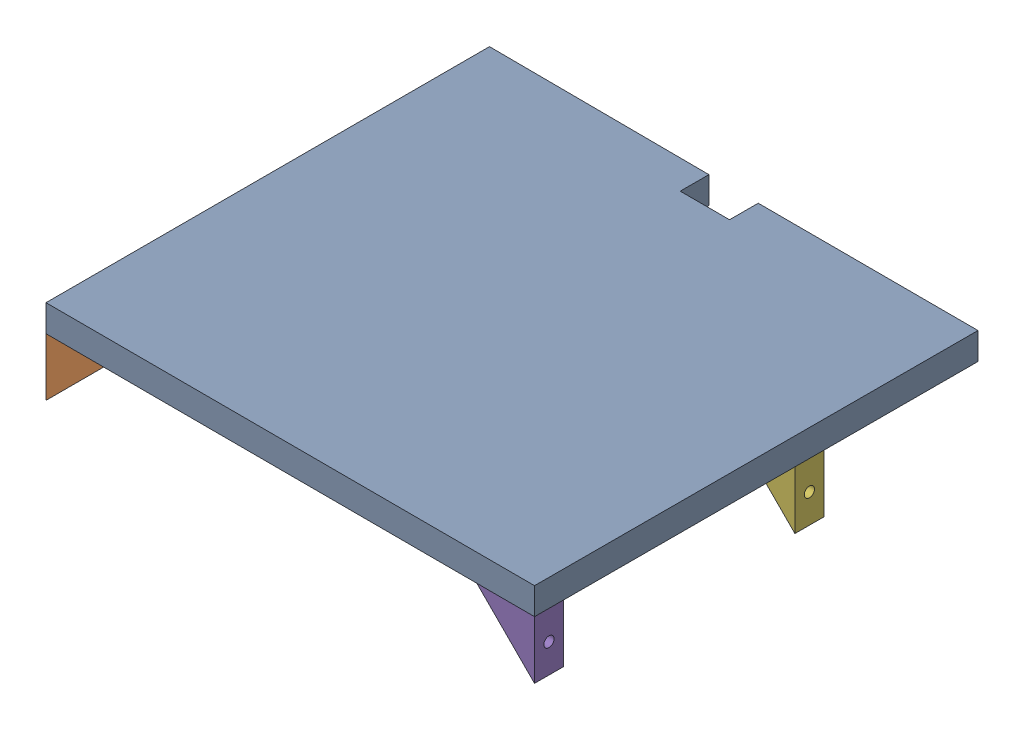
SolidWorks assembly body-top-electronics-plate, configuration Default. Lengths in mm.
Overall size (215.83 37.21 195.37).
7 component instances, 2 part files, 15 mates.
Components (placement in the parent):
- body-top-electronics-plate-1: body-top-electronics-plate [Default] at (150.8544 -10.5013 -261.1673) x (0.999999 0 0.001709) z (-0.001709 0 0.999999) size (215.5 11.81 195)
- body-top-electronics-bracket-1: body-top-electronics-bracket [Default] at (150.8651 -10.5013 -72.475) size (25.4 25.4 12.7)
- body-top-electronics-bracket-7: body-top-electronics-bracket [Default] at (150.8651 -10.5013 -186.775) size (25.4 25.4 12.7)
- body-top-electronics-bracket-8: body-top-electronics-bracket [Default] at (85.1809 -10.5013 -159.0477) x (-0.005146 0 0.999987) z (-0.999987 0 -0.005146) size (25.4 25.4 12.7)
- body-top-electronics-bracket-13: body-top-electronics-bracket [Default] at (149.6443 -10.5013 -84.9893) x (-0.999999 0 -0.001709) z (0.001709 0 -0.999999) size (25.4 25.4 12.7)
- body-top-electronics-bracket-14: body-top-electronics-bracket [Default] at (149.8397 -10.5013 -199.2892) x (-0.999999 0 -0.001709) z (0.001709 0 -0.999999) size (25.4 25.4 12.7)
- body-top-electronics-bracket-15: body-top-electronics-bracket [Default] at (197.2535 -10.5013 -158.6702) x (-0.001709 0 0.999999) z (-0.999999 0 -0.001709) size (25.4 25.4 12.7)
Mates (geometry in assembly coordinates):
- Coincident1: coincident anti-aligned: plane of body-top-electronics-plate-1 through (150.8544 81.5751 -261.1673) normal (0 -1 0); plane of body-top-electronics-bracket-1 through (42.6606 81.5751 -85.175) normal (0 1 0)
- Distance1: distance = 0 mm aligned: plane of body-top-electronics-bracket-1 through (42.6606 81.5751 -85.175) normal (-1 0 0); plane of body-top-electronics-plate-1 through (42.6606 93.3861 -267.4725) normal (-1 0 0)
- Coincident8: coincident anti-aligned: plane of body-top-electronics-plate-1 through (150.8544 81.5751 -261.1673) normal (0 -1 0); plane of body-top-electronics-bracket-7 through (42.6606 81.5751 -199.475) normal (0 1 0)
- Coincident9: coincident aligned: plane of body-top-electronics-plate-1 through (42.6606 93.3861 -267.4725) normal (-1 0 0); plane of body-top-electronics-bracket-7 through (42.6606 81.5751 -199.475) normal (-1 0 0)
- Coincident10: coincident anti-aligned: plane of body-top-electronics-plate-1 through (150.8544 81.5751 -261.1673) normal (0 -1 0); plane of body-top-electronics-bracket-8 through (98.4376 81.5751 -267.1854) normal (0 1 0)
- Coincident12: coincident aligned: plane of body-top-electronics-plate-1 through (139.6509 93.3861 -266.9734) normal (0.005146 0 -0.999987); plane of body-top-electronics-bracket-8 through (98.4376 81.5751 -267.1854) normal (0.005146 0 -0.999987)
- Distance2: distance = 101.6 mm anti-aligned: plane of body-top-electronics-bracket-1 through (150.8651 -10.5013 -85.175) normal (0 0 -1); plane of body-top-electronics-bracket-7 through (150.8651 -10.5013 -186.775) normal (0 0 1)
- Coincident23: coincident anti-aligned: plane of body-top-electronics-plate-1 through (150.8544 81.5751 -261.1673) normal (0 -1 0); plane of body-top-electronics-bracket-13 through (257.8269 81.5751 -72.1044) normal (0 1 0)
- Coincident24: coincident aligned: plane of body-top-electronics-plate-1 through (257.8269 93.3861 -72.1044) normal (0.999999 0 0.001709); plane of body-top-electronics-bracket-13 through (257.8269 81.5751 -72.1044) normal (0.999999 0 0.001709)
- Coincident25: coincident aligned: plane of body-top-electronics-plate-1 through (42.6606 93.3861 -72.4722) normal (-0.001709 0 0.999999); plane of body-top-electronics-bracket-13 through (149.6226 -10.5013 -72.2894) normal (-0.001709 0 0.999999)
- Coincident26: coincident anti-aligned: plane of body-top-electronics-plate-1 through (150.8544 81.5751 -261.1673) normal (0 -1 0); plane of body-top-electronics-bracket-14 through (258.0223 81.5751 -186.4042) normal (0 1 0)
- Coincident27: coincident aligned: plane of body-top-electronics-plate-1 through (257.8269 93.3861 -72.1044) normal (0.999999 0 0.001709); plane of body-top-electronics-bracket-14 through (258.0223 81.5751 -186.4042) normal (0.999999 0 0.001709)
- Distance7: distance = 101.6 mm anti-aligned: plane of body-top-electronics-bracket-13 through (149.6443 -10.5013 -84.9893) normal (0.001709 0 -0.999999); plane of body-top-electronics-bracket-14 through (149.818 -10.5013 -186.5892) normal (-0.001709 0 0.999999)
- Coincident29: coincident anti-aligned: plane of body-top-electronics-plate-1 through (150.8544 81.5751 -261.1673) normal (0 -1 0); plane of body-top-electronics-bracket-15 through (210.1384 81.5751 -266.8529) normal (0 1 0)
- Coincident30: coincident aligned: plane of body-top-electronics-plate-1 through (258.1597 93.3861 -266.7708) normal (0.001709 0 -0.999999); plane of body-top-electronics-bracket-15 through (210.1384 81.5751 -266.8529) normal (0.001709 0 -0.999999)
